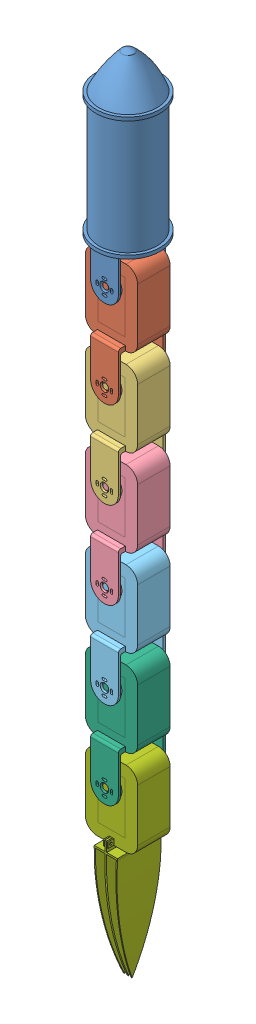
SolidWorks assembly test6_2, configuration 預設. Lengths in mm.
Overall size (55 691.27 55).
7 component instances, 7 part files, 25 mates.
Components (placement in the parent):
- base_link2-2: base_link2 [預設] at origin size (55 179.98 55)
- link1-1: link1 [預設] at (0 -157.7 0) x (0 1 0) z (0 0 -1) size (107 45 40.5)
- link2-1: link2 [預設] at (0 -232.4 0) x (0 1 0) z (0 0 -1) size (107 45 40.5)
- link3-2: link3 [預設] at (0 -307.1 0) x (0 1 0) z (0 0 -1) size (107 45 40.5)
- link4-1: link4 [預設] at (0 -381.8 0) x (0 1 0) z (0 0 -1) size (107 45 40.5)
- link5-1: link5 [預設] at (0 -456.5 0) x (0 1 0) z (0 0 -1) size (107 45 40.5)
- link6-1: link6 [預設] at (0 -456.2 0.5) x (0 1 0) z (0 0 -1) size (170.09 49.79 38.13)
Mates (geometry in assembly coordinates):
- 平行相距4: distance = 18.5 mm: plane of base_link2-2 through (0 -83 -18.5) normal (0 0 1); plane of assembly through (0 0 0) normal (0 0 1)
- 平行相距5: distance = 12 mm: plane of assembly through (0 0 0) normal (1 0 0); plane of base_link2-2 through (12 -53 18) normal (1 0 0)
- 平行相距6: distance = 50 mm: plane of assembly through (0 0 0) normal (0 1 0); plane of base_link2-2 through (0 -50 -0.25) normal (0 1 0)
- 同軸心2: concentric: cylinder of base_link2-2 through (0 -83 18) axis (0 0 1) radius 4; cylinder of link1-1 through (0 -83 14) axis (0 0 1) radius 2.5
- 同軸心3: concentric: cylinder of base_link2-2 through (0 -83 -20.5) axis (0 0 1) radius 4; cylinder of link1-1 through (0 -83 -19) axis (0 0 1) radius 2.5
- 平行1: parallel: plane of base_link2-2 through (12 -53 -20.5) normal (1 0 0); plane of link1-1 through (22.5 -127.7 -14) normal (1 0 0)
- 重合/共線/共點8: coincident: plane of base_link2-2 through (0 -83 -18.5) normal (0 0 1); plane of link1-1 through (0 -157.7 -18.5) normal (0 0 1)
- 同軸心4: concentric: cylinder of link1-1 through (0 -157.7 20) axis (0 0 -1) radius 3.7; cylinder of ? through (122.3295 -185.6512 7.75) axis (0 0 -1) radius 2.5
- 重合/共線/共點9: coincident: plane of link1-1 through (22.5 -127.7 -14) normal (1 0 0); plane of ?
- 重合/共線/共點10: coincident: plane of link1-1 through (0 -67.7653 20) normal (0 0 1); plane of ?
- 重合/共線/共點11: coincident: plane of link1-1 through (22.5 -127.7 -14) normal (1 0 0); plane of link2-1 through (22.5 -202.4 -14) normal (1 0 0)
- 同軸心5: concentric: cylinder of link1-1 through (0 -157.7 20) axis (0 0 -1) radius 3.7; cylinder of link2-1 through (0 -157.7 14) axis (0 0 1) radius 2.5
- 重合/共線/共點12: coincident: plane of link1-1 through (0 -67.7653 14) normal (0 0 1); plane of link2-1 through (0 -142.4653 14) normal (0 0 1)
- 重合/共線/共點14: coincident: plane of link2-1 through (22.5 -202.4 -14) normal (1 0 0); plane of link3-2 through (22.5 -277.1 -14) normal (1 0 0)
- 同軸心6: concentric: cylinder of link2-1 through (0 -232.4 -18.5) axis (0 0 -1) radius 4; cylinder of link3-2 through (0 -232.4 -19) axis (0 0 1) radius 2.5
- 重合/共線/共點15: coincident: plane of link2-1 through (0 -142.4653 -14) normal (0 0 -1); plane of link3-2 through (0 -217.1653 -14) normal (0 0 -1)
- 同軸心7: concentric: cylinder of link3-2 through (0 -307.1 20) axis (0 0 -1) radius 3.7; cylinder of link4-1 through (0 -307.1 14) axis (0 0 1) radius 2.5
- 重合/共線/共點16: coincident: plane of link3-2 through (22.5 -277.1 -14) normal (1 0 0); plane of link4-1 through (22.5 -351.8 -14) normal (1 0 0)
- 重合/共線/共點17: coincident: plane of link3-2 through (0 -217.1653 14) normal (0 0 1); plane of link4-1 through (0 -291.8653 14) normal (0 0 1)
- 重合/共線/共點18: coincident: plane of link4-1 through (22.5 -351.8 -14) normal (1 0 0); plane of link5-1 through (22.5 -426.5 -14) normal (1 0 0)
- 同軸心8: concentric: cylinder of link4-1 through (0 -381.8 20) axis (0 0 -1) radius 3.7; cylinder of link5-1 through (0 -381.8 14) axis (0 0 1) radius 2.5
- 重合/共線/共點19: coincident: plane of link4-1 through (0 -291.8653 14) normal (0 0 1); plane of link5-1 through (0 -366.5653 14) normal (0 0 1)
- 重合/共線/共點21: coincident: plane of link5-1 through (-22.5 -426.5 -14) normal (-1 0 0); plane of link6-1 through (-22.5 -501.2 -14) normal (-1 0 0)
- 同軸心9: concentric: cylinder of link5-1 through (0 -456.5 14) axis (0 0 1) radius 4; cylinder of link6-1 through (0 -456.5 14) axis (0 0 1) radius 2.5
- 重合/共線/共點22: coincident: plane of link5-1 through (0 -366.5653 14) normal (0 0 1); plane of link6-1 through (0 -441.2653 14) normal (0 0 1)
